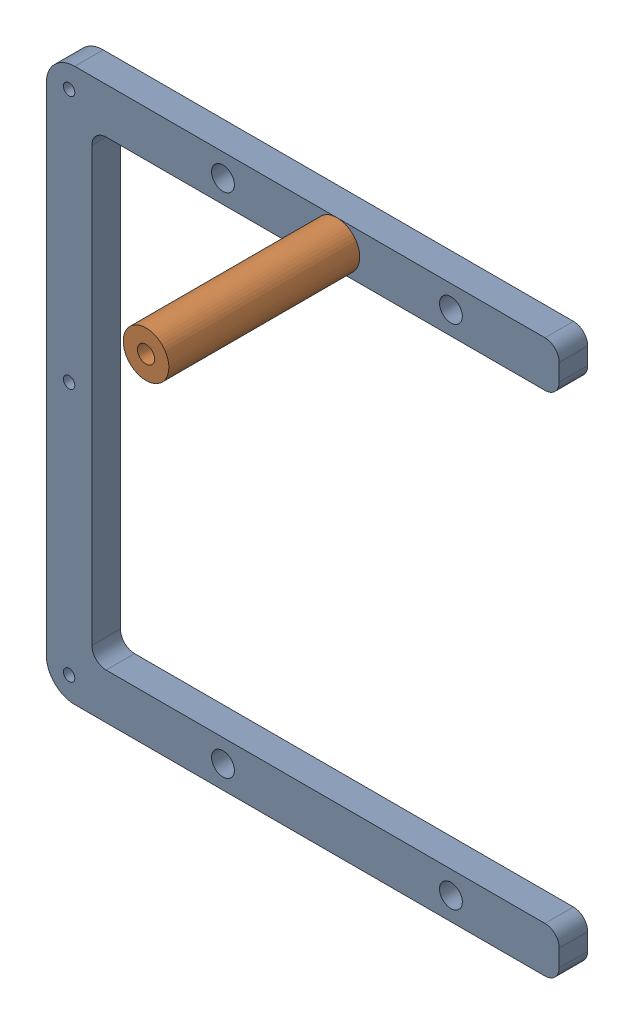
SolidWorks assembly CoperBus, configuration Default. Lengths in mm.
Overall size (90 98.23 38.5).
2 component instances, 2 part files, 2 mates.
Components (placement in the parent):
- Bus1-1: Bus1 [Default] at origin size (90 97 5)
- Bus1_part-1: Bus1_part [Default] at (51 44.5 38.5) x (-0.923728 -0.383049 0) z (0 0 -1) size (8 8 38.5)
Mates (geometry in assembly coordinates):
- Concentric1: concentric anti-aligned: circle of Bus1-1; circle of Bus1_part-1
- Coincident4: coincident anti-aligned: plane of Bus1-1 through (5 -43.5 5) normal (0 0 1); plane of Bus1_part-1 through (51 44.5 5) normal (0 0 -1)
